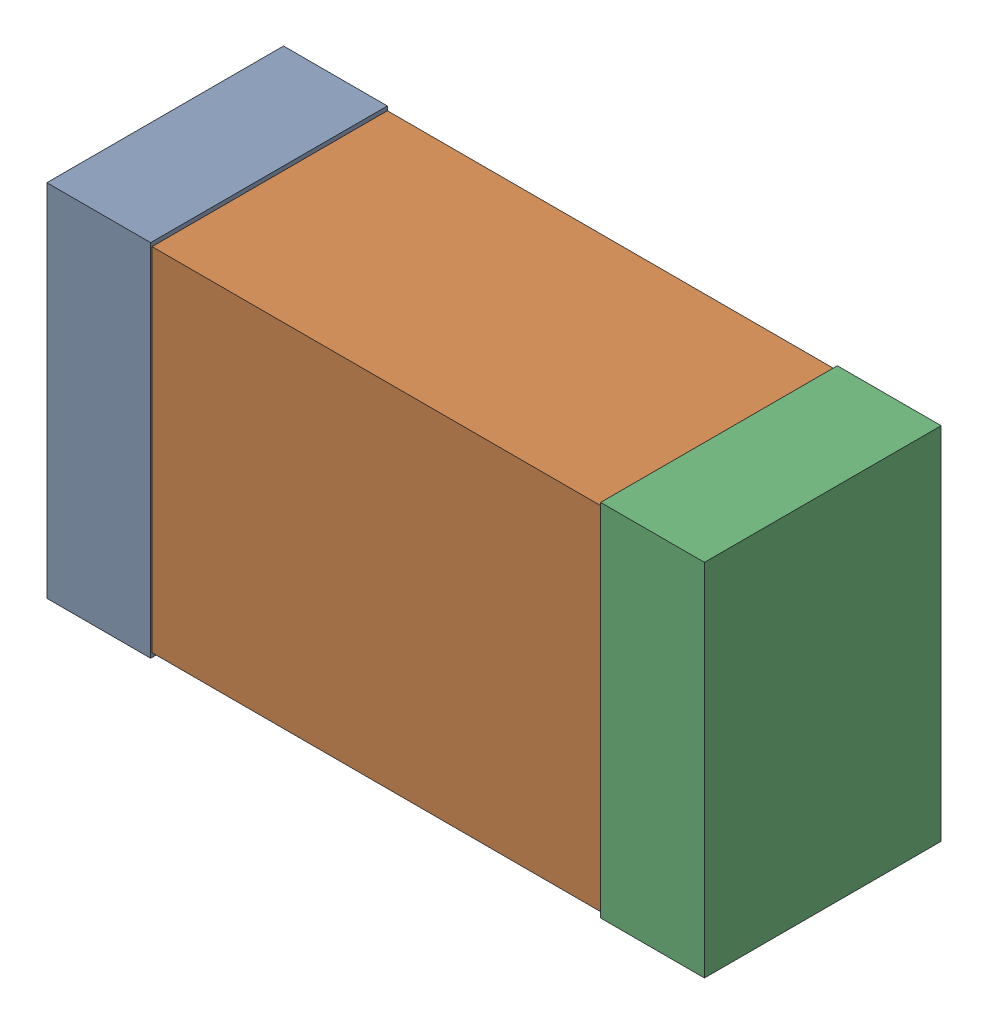
SolidWorks assembly C13_Motor_7Kanaloa_v2.0.0_Motor, configuration Default. Lengths in mm.
Overall size (2.38 1.3 0.85).
6 component instances, 2 part files, 0 mates.
Components (placement in the parent):
- 352877648-1: 352877648 [Default] at (102.314 142.24 0) size (0.38 1.3 0.85)
  - Extruded_14-1: Extruded_14 [Default] at origin size (0.38 1.3 0.85)
- 352877392-1: 352877392 [Default] at (103.314 142.24 0) size (2.2 1.27 0.85)
  - Extruded_15-1: Extruded_15 [Default] at origin size (2.2 1.27 0.85)
- 352877648-2: 352877648 [Default] at (104.314 142.24 0) size (0.38 1.3 0.85)
  - Extruded_14-1: Extruded_14 [Default] at origin size (0.38 1.3 0.85)
